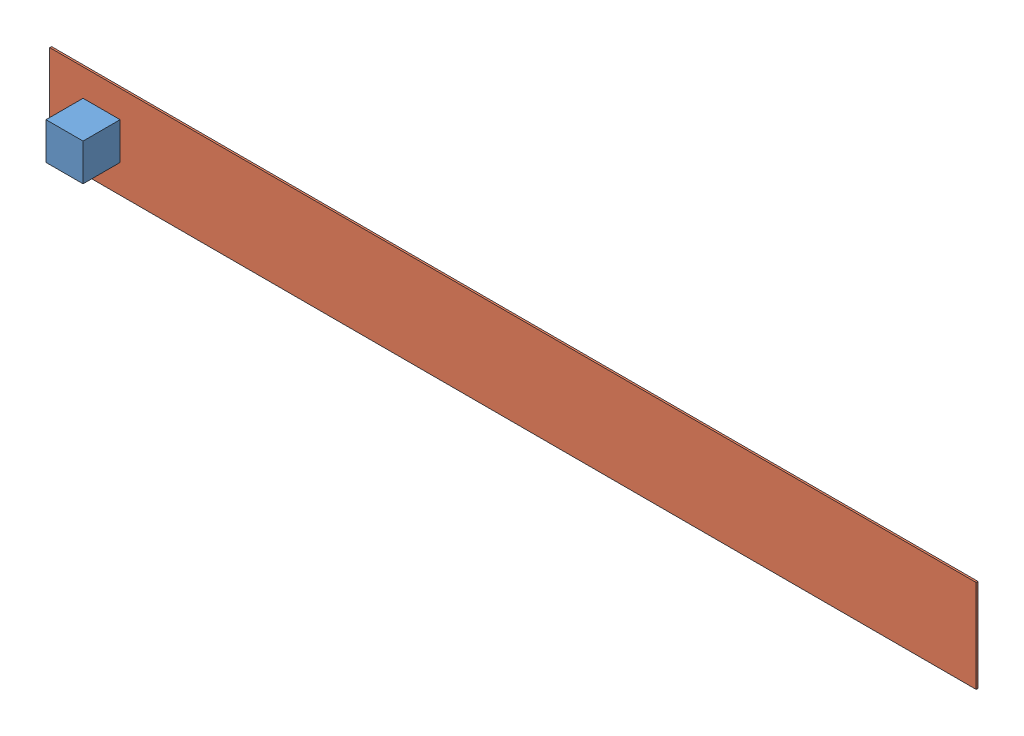
SolidWorks assembly AssemblageCubePlateauProf, configuration Défaut. Lengths in mm.
Overall size (5000 500 210).
2 component instances, 2 part files, 1 mates.
Components (placement in the parent):
- cube-1: cube [Défaut] at (-2258.5507 -15.6363 205) size (200 200 200)
- plateau-1: plateau [Défaut] at (-2438.3121 -168.7585 195) size (5000 500 10)
Mates (geometry in assembly coordinates):
- Coïncidente1: coincident anti-aligned: plane of cube-1 through (-2258.5507 -15.6363 205) normal (0 0 -1); plane of plateau-1 through (-2438.3121 -168.7585 205) normal (0 0 1)
